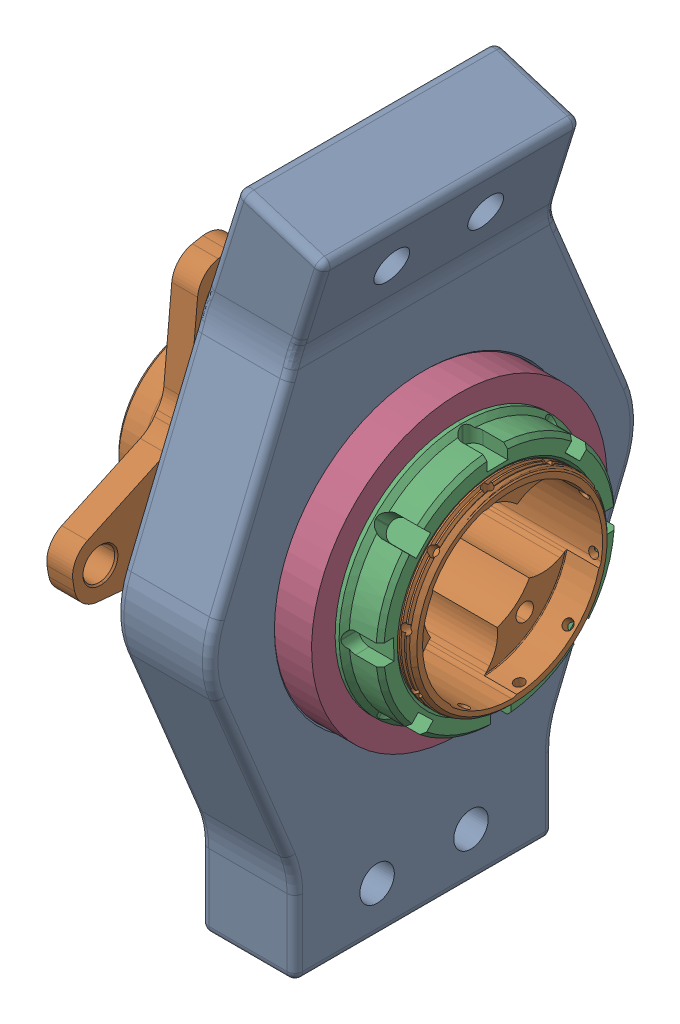
SolidWorks assembly 230028, configuration Default. Lengths in mm.
Overall size (101.92 211.1 136.73).
5 component instances, 4 part files, 8 mates.
Components (placement in the parent):
- 230013-1: 230013 [Default] at origin size (38.73 211.1 136.73)
- 230014-1: 230014 [Default] at (43.1025 0 0) x (-1 0 0) z (0 0.985491 0.169729) size (101.92 117.35 117.35)
- 230015-1: 230015 [Default] at (38.975 0 0) x (-1 0 0) z (0 -0.999879 -0.015564) size (12.7 79.38 79.38)
- 230016-1: 230016 [Default] at (16.75 0 0) x (1 0 0) z (0 0.227438 0.973792) size (19.05 94.42 94.42)
- 230016-2: 230016 [Default] at (-16.75 0 0) x (1 0 0) z (0 0.227438 0.973792) size (19.05 94.42 94.42)
Mates (geometry in assembly coordinates):
- Concentric1: concentric aligned: cylinder of WheelKnuckle_Back-1 through (-15 0 0) axis (1 0 0) radius 47.3122; cylinder of D5580.step-1 through (43.1025 0 0) axis (1 0 0) radius 31.75
- Coincident1: coincident anti-aligned: plane of WheelKnuckle_Back-1 through (-15 0 0) normal (-1 0 0); plane of D5580.step-1 through (-15 -5.6476 32.7912) normal (1 0 0)
- Screw1: screw = 1 aligned: cylinder of D5580.step-1 through (43.1025 0 0) axis (1 0 0) radius 31.6865; cylinder of D5239.step-1 through (38.975 0 0) axis (1 0 0) radius 31.242
- Tangent1: tangent anti-aligned: cylinder of D5580.step-1 through (40.5625 34.4497 -65.417) axis (0 -0.465955 0.884808) radius 1.5875; plane of D5239.step-1 through (38.975 0.506 -32.5081) normal (1 0 0)
- Concentric2: concentric anti-aligned: cylinder of D5580.step-1 through (43.1025 0 0) axis (1 0 0) radius 31.75; cylinder of Rear Ball Bearing (L610549)-1 through (26.275 0 0) axis (-1 0 0) radius 47.2122
- Coincident2: coincident anti-aligned: plane of D5239.step-1 through (26.275 0.6177 -39.6827) normal (-1 0 0); plane of Rear Ball Bearing (L610549)-1 through (26.275 0 0) normal (1 0 0)
- Concentric3: concentric anti-aligned: cylinder of D5580.step-1 through (43.1025 0 0) axis (1 0 0) radius 31.75; cylinder of Rear Ball Bearing (L610549)-2 through (-7.225 0 0) axis (-1 0 0) radius 31.75
- Width1: width anti-aligned: plane of Rear Ball Bearing (L610549)-1 through (26.275 0 0) normal (1 0 0); plane of WheelKnuckle_Back-1 through (-26.275 0 0) normal (-1 0 0); plane of Rear Ball Bearing (L610549)-2 through (-15 0 0) normal (-1 0 0); plane of WheelKnuckle_Back-1 through (15 0 0) normal (1 0 0)
